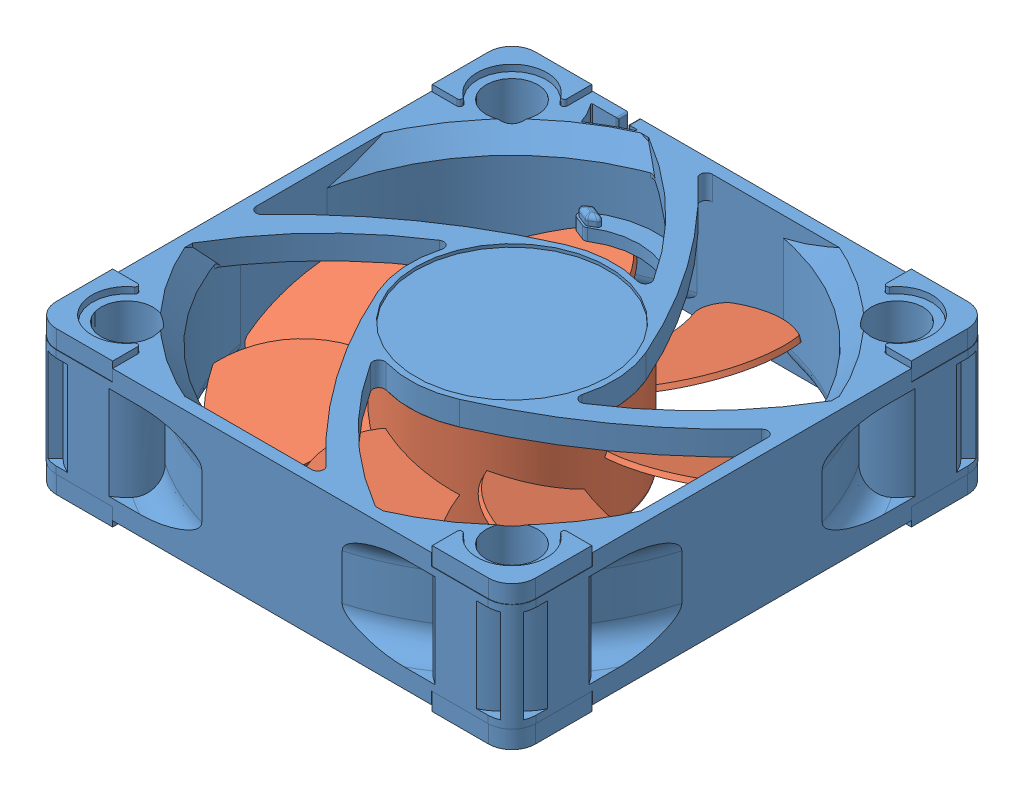
SolidWorks assembly NF-A4x10 Fan, configuration Default. Lengths in mm.
Overall size (40.14 12 40.18).
3 component instances, 2 part files, 0 mates.
Components (placement in the parent):
- NF-A4x10_Noctua_40mm.step-1: NF-A4x10_Noctua_40mm.step [Default] at origin size (40.14 12 40.18)
  - Noctua-NF-A4x10 v1.step-1: Noctua-NF-A4x10 v1.step [Default] at (0 -5.2451 0) x (1 0 0) z (0 -1 0) size (40.14 40.18 12)
  - Noctua nf-a8-pwm fan 80x80x25 v2.step-1: Noctua nf-a8-pwm fan 80x80x25 v2.step [Default] at (0 -0.546 0) x (1 0 0) z (0 -1 0) size (36.32 36.48 8.8)
